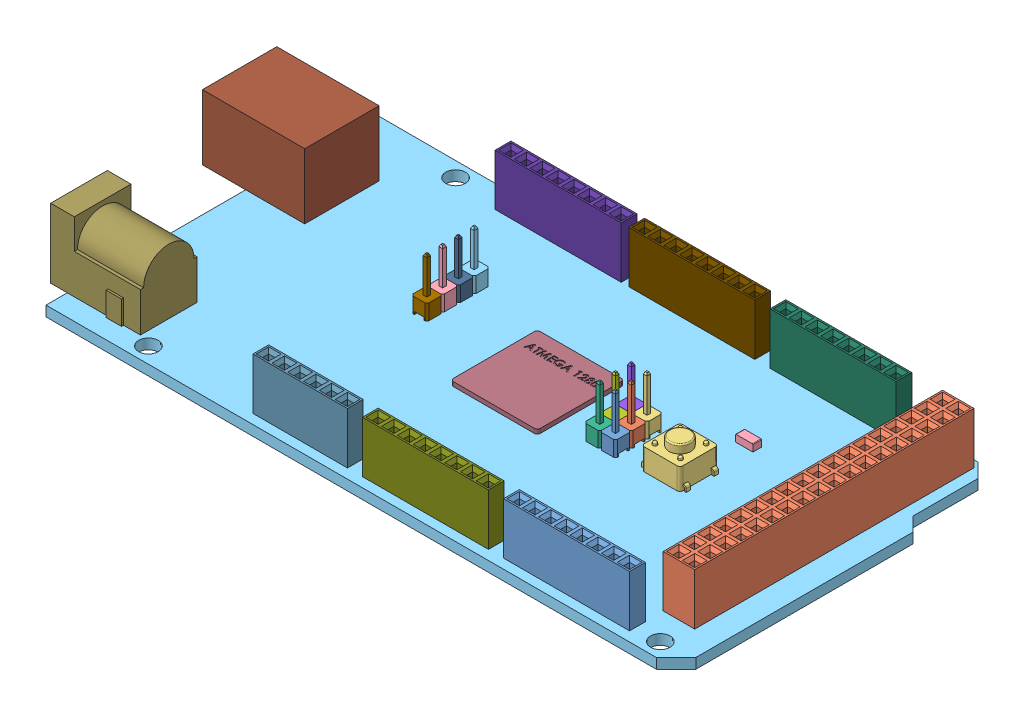
SolidWorks assembly ArduinoMega2560R3, configuration Default. Lengths in mm.
Overall size (108.58 14.9 53.21).
23 component instances, 23 part files, 0 mates.
Components (placement in the parent):
- Part4-1: Part4 [Default] at origin size (2.54 9.3 2.54)
- Part6-1: Part6 [Default] at origin size (2.54 9.3 2.54)
- Part8-1: Part8 [Default] at origin size (2.54 9.3 2.54)
- Part10-1: Part10 [Default] at origin size (2.54 9.3 2.54)
- Part12-1: Part12 [Default] at origin size (2.54 9.3 2.54)
- Part14-1: Part14 [Default] at origin size (2.54 9.3 2.54)
- Part16-1: Part16 [Default] at origin size (2.54 9.3 2.54)
- Part18-1: Part18 [Default] at origin size (2.54 9.3 2.54)
- Part20-1: Part20 [Default] at origin size (2.54 9.3 2.54)
- Part22-1: Part22 [Default] at origin size (2.54 9.3 2.54)
- Part24-1: Part24 [Default] at origin size (16.5 14.22 14.86)
- Part26-1: Part26 [Default] at origin size (14.48 14.78 9.47)
- Part28-1: Part28 [Default] at origin size (14 0.7 14)
- Part30-1: Part30 [Default] at origin size (15.24 8.3 2.54)
- Part32-1: Part32 [Default] at origin size (20.32 8.3 2.54)
- Part34-1: Part34 [Default] at origin size (20.32 8.3 2.54)
- Part36-1: Part36 [Default] at origin size (20.32 8.3 2.54)
- Part38-1: Part38 [Default] at origin size (20.32 8.3 2.54)
- Part40-1: Part40 [Default] at origin size (20.32 8.3 2.54)
- Part42-1: Part42 [Default] at origin size (5.08 8.3 45.04)
- Part44-1: Part44 [Default] at origin size (7.9 7.35 6.2)
- Part46-1: Part46 [Default] at origin size (2.8 1.12 1.4)
- PCB-FIXED-1: PCB-FIXED [Default] at (0.1155 -4.6912 4.2705) x (1 0 0) z (0 0 -1) size (101.6 1.65 53.21)
